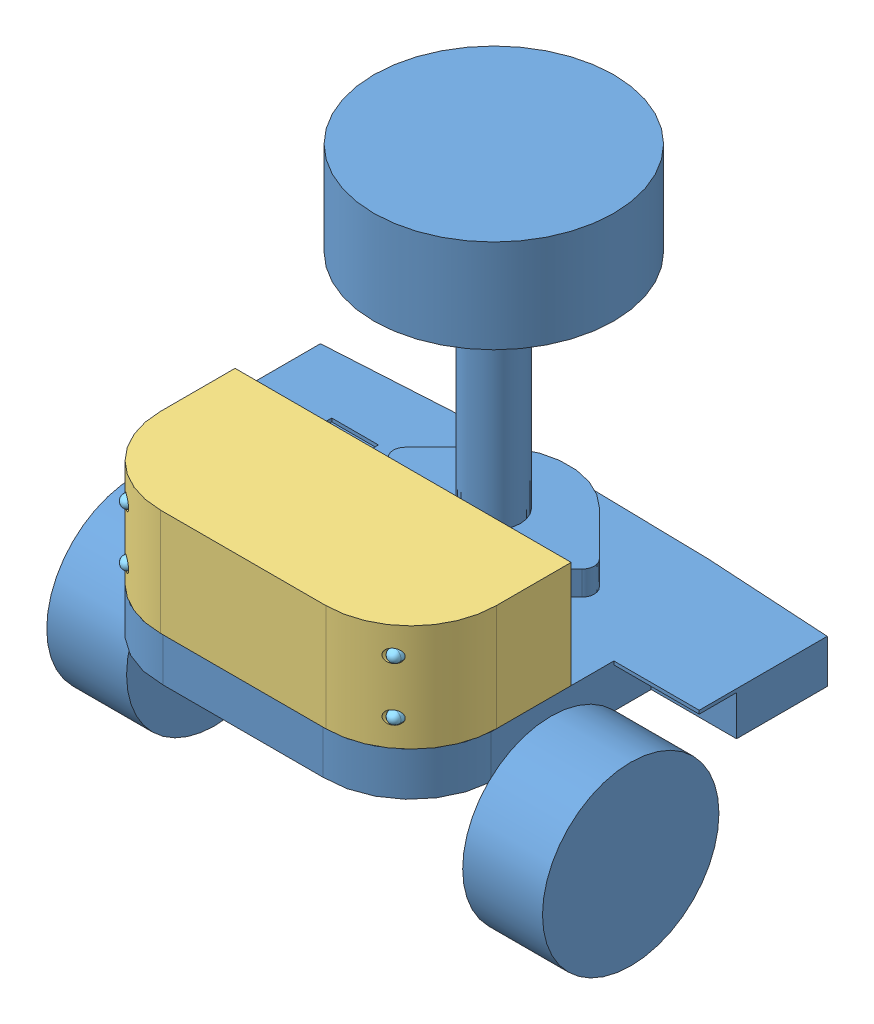
SolidWorks assembly Test Assembly, configuration Default. Lengths in mm.
Overall size (80.01 25.4 38.1).
8 component instances, 5 part files, 13 mates.
Components (placement in the parent):
- REAR ACCESSORY-1: REAR ACCESSORY [Default] at (-79.5333 13.0209 64.8228) size (120.65 126.74 88.28) (hidden)
- gp2d12-1: gp2d12 [Default] at (-79.1744 21.9212 49.7353) x (-1 0 0) z (0 0 1) size (44.5 18.9 13.5)
- VEHICLE, BASEPLATE-1: VEHICLE, BASEPLATE [Default] at (-79.5333 13.8337 64.8228) size (80.01 25.4 38.1)
- SMD Buzzer-1: SMD Buzzer [Default] at (-79.4357 15.4212 41.3375) size (9.15 4 10.15)
- SENSOR, COLOR LED-1: SENSOR, COLOR LED [Default] at (-99.544 32.8837 21.5956) x (0 0 -1) z (1 0 0) size (5.83 3.66 3.66)
- SENSOR, COLOR LED-2: SENSOR, COLOR LED [Default] at (-99.544 20.1837 21.5956) x (0 0 -1) z (1 0 0) size (5.83 3.66 3.66)
- SENSOR, COLOR LED-3: SENSOR, COLOR LED [Default] at (-36.044 32.8837 21.5956) x (0 0 -1) z (1 0 0) size (5.83 3.66 3.66)
- SENSOR, COLOR LED-4: SENSOR, COLOR LED [Default] at (-36.044 20.1837 21.5956) x (0 0 -1) z (1 0 0) size (5.83 3.66 3.66)
Mates (geometry in assembly coordinates):
- Coincident3: coincident anti-aligned: plane of REAR ACCESSORY-1 through (-99.2573 13.8337 44.514) normal (0 1 0); plane of VEHICLE, BASEPLATE-1 through (-99.2183 13.8337 44.5028) normal (0 -1 0)
- Coincident4: coincident aligned: plane of REAR ACCESSORY-1 through (-60.4833 13.8337 64.8228) normal (0 0 1); plane of VEHICLE, BASEPLATE-1 through (-99.2183 39.2337 64.8228) normal (0 0 1)
- Coincident5: coincident anti-aligned: plane of gp2d12-1 through (-64.4244 15.4212 56.9353) normal (0 -1 0); plane of VEHICLE, BASEPLATE-1 through (-99.2183 15.4212 44.5028) normal (0 1 0)
- Coincident6: coincident anti-aligned: plane of gp2d12-1 through (-72.6994 25.5212 63.2353) normal (0 0 1); plane of VEHICLE, BASEPLATE-1 through (-99.2183 39.2337 63.2353) normal (0 0 -1)
- Coincident7: coincident anti-aligned: plane of VEHICLE, BASEPLATE-1 through (-99.2183 15.4212 44.5028) normal (0 1 0); plane of SMD Buzzer-1 through (-79.4357 15.4212 41.3375) normal (0 -1 0)
- Concentric3: concentric anti-aligned: cylinder of VEHICLE, BASEPLATE-1 through (-111.2833 32.8837 26.7218) axis (0 0 1) radius 1.5875; cylinder of SENSOR, COLOR LED-1 through (-111.2833 32.8837 60.464) axis (0 0 -1) radius 1.4605
- Concentric4: concentric anti-aligned: cylinder of VEHICLE, BASEPLATE-1 through (-111.2833 20.1837 26.7218) axis (0 0 1) radius 1.5875; cylinder of SENSOR, COLOR LED-2 through (-111.2833 20.1837 60.464) axis (0 0 -1) radius 1.4605
- Coincident8: coincident aligned: plane of SENSOR, COLOR LED-1 through (-109.4326 31.033 56.0952) normal (0 0 -1); plane of SENSOR, COLOR LED-2 through (-109.4326 18.333 56.0952) normal (0 0 -1)
- Concentric5: concentric anti-aligned: cylinder of VEHICLE, BASEPLATE-1 through (-47.7833 32.8837 26.7218) axis (0 0 1) radius 1.5875; cylinder of SENSOR, COLOR LED-3 through (-47.7833 32.8837 60.464) axis (0 0 -1) radius 1.4605
- Concentric6: concentric anti-aligned: cylinder of VEHICLE, BASEPLATE-1 through (-47.7833 20.1837 26.7218) axis (0 0 1) radius 1.5875; cylinder of SENSOR, COLOR LED-4 through (-47.7833 20.1837 60.464) axis (0 0 -1) radius 1.4605
- Coincident9: coincident aligned: plane of SENSOR, COLOR LED-3 through (-45.9326 31.033 56.0952) normal (0 0 -1); plane of SENSOR, COLOR LED-4 through (-45.9326 18.333 56.0952) normal (0 0 -1)
- Coincident10: coincident aligned: plane of SENSOR, COLOR LED-2 through (-109.4326 18.333 56.0952) normal (0 0 -1); plane of SENSOR, COLOR LED-3 through (-45.9326 31.033 56.0952) normal (0 0 -1)
- Coincident11: coincident aligned: plane of REAR ACCESSORY-1 through (-39.5283 13.8337 45.7728) normal (1 0 0); plane of VEHICLE, BASEPLATE-1 through (-39.5283 39.2337 26.7228) normal (1 0 0)
